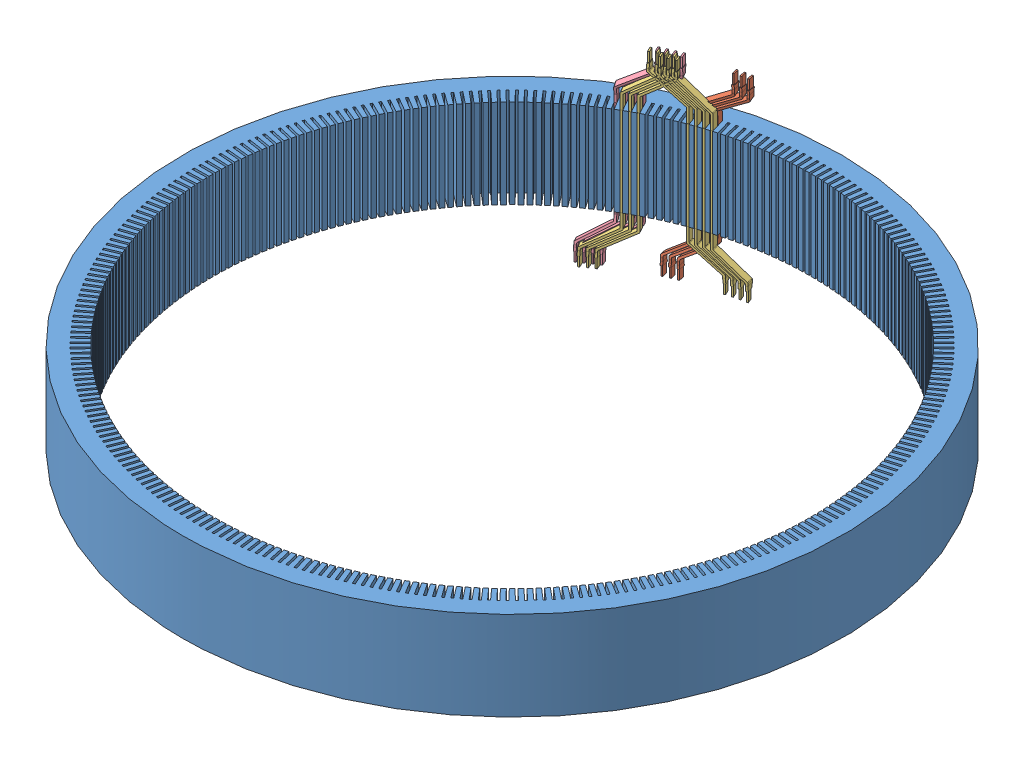
SolidWorks assembly Winding_Diagram_PhaseA, configuration Default. Lengths in mm.
Overall size (6858 2030.15 6858).
15 component instances, 4 part files, 20 mates.
Components (placement in the parent):
- laminasyon35mm_Ns300_Slot22_2022_11_17-1: laminasyon35mm_Ns300_Slot22_2022_11_17 [Default] at (2957.6152 2710.3041 5330.1185) size (6858 925 6858)
- Simetrik Bobin_Aynalanmış Versiyon_Rotordan uzak (BOTTOM) kısım_v03.stp-4: Simetrik Bobin_Aynalanmış Versiyon_Rotordan uzak (BOTTOM) kısım_v03.stp [Default] at (2028.1885 3172.8041 2251.7088) x (0.957319 0 -0.289032) z (0 -1 0) size (612.07 121.36 2007.43)
- Simetrik Bobin_Aynalanmış Versiyon_Rotordan uzak (BOTTOM) kısım_v03.stp-5: Simetrik Bobin_Aynalanmış Versiyon_Rotordan uzak (BOTTOM) kısım_v03.stp [Default] at (1963.923 3172.8041 2271.8484) x (0.951057 0 -0.309017) z (0 -1 0) size (612.07 121.36 2007.43)
- Simetrik Bobin_Aynalanmış Versiyon_Rotordan uzak (BOTTOM) kısım_v03.stp-6: Simetrik Bobin_Aynalanmış Versiyon_Rotordan uzak (BOTTOM) kısım_v03.stp [Default] at (1900.0934 3172.8041 2293.3295) x (0.944376 0 -0.328867) z (0 -1 0) size (612.07 121.36 2007.43)
- Asimetrik Bobin_Rotora yakın (TOP) kısım_v03.stp-5: Asimetrik Bobin_Rotora yakın (TOP) kısım_v03.stp [Default] at (2050.6607 3172.8041 2326.1404) x (0.957319 0 -0.289032) z (0 -1 0) size (644.87 70.38 2007.43)
- Asimetrik Bobin_Rotora yakın (TOP) kısım_v03.stp-6: Asimetrik Bobin_Rotora yakın (TOP) kısım_v03.stp [Default] at (1987.9491 3172.8041 2345.7931) x (0.951057 0 -0.309017) z (0 -1 0) size (644.87 70.38 2007.43)
- Asimetrik Bobin_Rotora yakın (TOP) kısım_v03.stp-7: Asimetrik Bobin_Rotora yakın (TOP) kısım_v03.stp [Default] at (1925.6628 3172.8041 2366.7547) x (0.944376 0 -0.328867) z (0 -1 0) size (644.87 70.38 2007.43)
- Asimetrik Bobin_Rotora yakın (TOP) kısım_v03.stp-8: Asimetrik Bobin_Rotora yakın (TOP) kısım_v03.stp [Default] at (1863.8291 3172.8041 2389.0162) x (0.937282 0 -0.348572) z (0 -1 0) size (644.87 70.38 2007.43)
- Asimetrik Bobin_Aynalanmış Versiyon_Rotordan uzak (BOTTOM) kısım_v03.stp-2: Asimetrik Bobin_Aynalanmış Versiyon_Rotordan uzak (BOTTOM) kısım_v03.stp [Default] at (1467.8148 3172.8041 2480.3931) x (0.886204 0 -0.463296) z (0 -1 0) size (644.87 125.4 2007.43)
- Asimetrik Bobin_Aynalanmış Versiyon_Rotordan uzak (BOTTOM) kısım_v03.stp-3: Asimetrik Bobin_Aynalanmış Versiyon_Rotordan uzak (BOTTOM) kısım_v03.stp [Default] at (1408.4614 3172.8041 2512.2181) x (0.876307 0 -0.481754) z (0 -1 0) size (644.87 125.4 2007.43)
- Asimetrik Bobin_Aynalanmış Versiyon_Rotordan uzak (BOTTOM) kısım_v03.stp-4: Asimetrik Bobin_Aynalanmış Versiyon_Rotordan uzak (BOTTOM) kısım_v03.stp [Default] at (1349.7875 3172.8041 2545.2792) x (0.866025 0 -0.5) z (0 -1 0) size (644.87 125.4 2007.43)
- Asimetrik Bobin_Aynalanmış Versiyon_Rotordan uzak (BOTTOM) kısım_v03.stp-5: Asimetrik Bobin_Aynalanmış Versiyon_Rotordan uzak (BOTTOM) kısım_v03.stp [Default] at (1291.8188 3172.8041 2579.5617) x (0.855364 0 -0.518027) z (0 -1 0) size (644.87 125.4 2007.43)
- Asimetrik Bobin_Rotora yakın (TOP) kısım_v03.stp-9: Asimetrik Bobin_Rotora yakın (TOP) kısım_v03.stp [Default] at (1503.836 3172.8041 2549.2954) x (0.886204 0 -0.463296) z (0 1 0) size (644.87 70.38 2007.43)
- Asimetrik Bobin_Rotora yakın (TOP) kısım_v03.stp-10: Asimetrik Bobin_Rotora yakın (TOP) kısım_v03.stp [Default] at (1445.9177 3172.8041 2580.351) x (0.876307 0 -0.481754) z (0 1 0) size (644.87 70.38 2007.43)
- Asimetrik Bobin_Rotora yakın (TOP) kısım_v03.stp-11: Asimetrik Bobin_Rotora yakın (TOP) kısım_v03.stp [Default] at (1388.6625 3172.8041 2612.6127) x (0.866025 0 -0.5) z (0 1 0) size (644.87 70.38 2007.43)
Mates (geometry in assembly coordinates):
- Parallel6: parallel anti-aligned: plane of laminasyon35mm_Ns300_Slot22_2022_11_17-1 through (2018.0363 3635.3041 2218.083) normal (0.289032 0 0.957319); plane of Simetrik Bobin_Aynalanmış Versiyon_Rotordan uzak (BOTTOM) kısım_v03.stp-4 through (2018.0363 3172.8041 2218.083) normal (-0.289032 0 -0.957319)
- Parallel7: parallel anti-aligned: plane of laminasyon35mm_Ns300_Slot22_2022_11_17-1 through (2968.1457 3635.3041 5326.9392) normal (-0.957319 0 0.289032); plane of Simetrik Bobin_Aynalanmış Versiyon_Rotordan uzak (BOTTOM) kısım_v03.stp-4 through (2028.3753 2710.3041 2214.9614) normal (0.957319 0 -0.289032)
- Distance8: distance = 0.2 mm anti-aligned: plane of laminasyon35mm_Ns300_Slot22_2022_11_17-1 through (2968.1457 3635.3041 5326.9392) normal (-0.957319 0 0.289032); plane of Simetrik Bobin_Aynalanmış Versiyon_Rotordan uzak (BOTTOM) kısım_v03.stp-4 through (2028.3753 2710.3041 2214.9614) normal (0.957319 0 -0.289032)
- Coincident14: coincident anti-aligned: plane of laminasyon35mm_Ns300_Slot22_2022_11_17-1 through (2018.0363 3635.3041 2218.083) normal (0.289032 0 0.957319); plane of Simetrik Bobin_Aynalanmış Versiyon_Rotordan uzak (BOTTOM) kısım_v03.stp-4 through (2018.0363 3172.8041 2218.083) normal (-0.289032 0 -0.957319)
- Distance9: distance = 0.2 mm: line of Simetrik Bobin_Aynalanmış Versiyon_Rotordan uzak (BOTTOM) kısım_v03.stp-4 through (2028.3753 3635.3041 2214.9614) axis (0.289032 0 0.957319); line of laminasyon35mm_Ns300_Slot22_2022_11_17-1 through (2028.5668 3635.3041 2214.9036) axis (0.289032 0 0.957319)
- Parallel10: parallel anti-aligned: plane of Simetrik Bobin_Aynalanmış Versiyon_Rotordan uzak (BOTTOM) kısım_v03.stp-4 through (2038.3408 3172.8041 2285.3347) normal (0.289032 0 0.957319); plane of Asimetrik Bobin_Rotora yakın (TOP) kısım_v03.stp-5 through (2040.5085 3172.8041 2292.5146) normal (-0.289032 0 -0.957319)
- Distance10: distance = 7.5 mm anti-aligned: plane of Asimetrik Bobin_Rotora yakın (TOP) kısım_v03.stp-5 through (2040.5085 3172.8041 2292.5146) normal (-0.289032 0 -0.957319); plane of Simetrik Bobin_Aynalanmış Versiyon_Rotordan uzak (BOTTOM) kısım_v03.stp-4 through (2038.3408 3172.8041 2285.3347) normal (0.289032 0 0.957319)
- Parallel11: parallel anti-aligned: plane of laminasyon35mm_Ns300_Slot22_2022_11_17-1 through (2968.1457 3635.3041 5326.9392) normal (-0.957319 0 0.289032); plane of Asimetrik Bobin_Rotora yakın (TOP) kısım_v03.stp-5 through (2050.8476 2710.3041 2289.393) normal (0.957319 0 -0.289032)
- Distance11: distance = 0.2 mm anti-aligned: plane of Asimetrik Bobin_Rotora yakın (TOP) kısım_v03.stp-5 through (2050.8476 2710.3041 2289.393) normal (0.957319 0 -0.289032); plane of laminasyon35mm_Ns300_Slot22_2022_11_17-1 through (2968.1457 3635.3041 5326.9392) normal (-0.957319 0 0.289032)
- Distance12: distance = 0.2 mm: line of Asimetrik Bobin_Rotora yakın (TOP) kısım_v03.stp-5 through (2051.1164 3635.3041 2290.2833) axis (0.289032 0 0.957319); line of laminasyon35mm_Ns300_Slot22_2022_11_17-1 through (2028.5668 3635.3041 2214.9036) axis (0.289032 0 0.957319)
- Parallel13: parallel anti-aligned: plane of laminasyon35mm_Ns300_Slot22_2022_11_17-1 through (1451.5415 3635.3041 2449.2652) normal (0.463296 0 0.886204); plane of Asimetrik Bobin_Aynalanmış Versiyon_Rotordan uzak (BOTTOM) kısım_v03.stp-2 through (1451.5415 3172.8041 2449.2652) normal (-0.463296 0 -0.886204)
- Parallel14: parallel anti-aligned: plane of laminasyon35mm_Ns300_Slot22_2022_11_17-1 through (2967.3634 3635.3041 5325.0223) normal (-0.886204 0 0.463296); plane of Asimetrik Bobin_Aynalanmış Versiyon_Rotordan uzak (BOTTOM) kısım_v03.stp-2 through (1461.1125 2710.3041 2444.2616) normal (0.886204 0 -0.463296)
- Coincident23: coincident anti-aligned: plane of laminasyon35mm_Ns300_Slot22_2022_11_17-1 through (1451.5415 3635.3041 2449.2652) normal (0.463296 0 0.886204); plane of Asimetrik Bobin_Aynalanmış Versiyon_Rotordan uzak (BOTTOM) kısım_v03.stp-2 through (1451.5415 3172.8041 2449.2652) normal (-0.463296 0 -0.886204)
- Distance13: distance = 0.2 mm anti-aligned: plane of laminasyon35mm_Ns300_Slot22_2022_11_17-1 through (2967.3634 3635.3041 5325.0223) normal (-0.886204 0 0.463296); plane of Asimetrik Bobin_Aynalanmış Versiyon_Rotordan uzak (BOTTOM) kısım_v03.stp-2 through (1461.1125 2710.3041 2444.2616) normal (0.886204 0 -0.463296)
- Distance14: distance = 0.2 mm: line of Asimetrik Bobin_Aynalanmış Versiyon_Rotordan uzak (BOTTOM) kısım_v03.stp-2 through (1461.5434 3635.3041 2445.0858) axis (0.463296 0 0.886204); line of laminasyon35mm_Ns300_Slot22_2022_11_17-1 through (1461.2897 3635.3041 2444.169) axis (0.463296 0 0.886204)
- Parallel16: parallel anti-aligned: plane of Asimetrik Bobin_Aynalanmış Versiyon_Rotordan uzak (BOTTOM) kısım_v03.stp-2 through (1484.088 3172.8041 2511.521) normal (0.463296 0 0.886204); plane of Asimetrik Bobin_Rotora yakın (TOP) kısım_v03.stp-9 through (1487.5628 3172.8041 2518.1675) normal (-0.463296 0 -0.886204)
- Parallel17: parallel anti-aligned: plane of laminasyon35mm_Ns300_Slot22_2022_11_17-1 through (2967.3634 3635.3041 5325.0223) normal (-0.886204 0 0.463296); plane of Asimetrik Bobin_Rotora yakın (TOP) kısım_v03.stp-9 through (1529.6803 3635.3041 2575.4197) normal (0.886204 0 -0.463296)
- Distance15: distance = 0.2 mm anti-aligned: plane of Asimetrik Bobin_Rotora yakın (TOP) kısım_v03.stp-9 through (1529.6803 3635.3041 2575.4197) normal (0.886204 0 -0.463296); plane of laminasyon35mm_Ns300_Slot22_2022_11_17-1 through (2967.3634 3635.3041 5325.0223) normal (-0.886204 0 0.463296)
- Distance16: distance = 0.2 mm: line of Asimetrik Bobin_Rotora yakın (TOP) kısım_v03.stp-9 through (1497.5646 3635.3041 2513.9881) axis (0.463296 0 0.886204); line of laminasyon35mm_Ns300_Slot22_2022_11_17-1 through (1461.2897 3635.3041 2444.169) axis (0.463296 0 0.886204)
- Distance17: distance = 7.5 mm anti-aligned: plane of Asimetrik Bobin_Aynalanmış Versiyon_Rotordan uzak (BOTTOM) kısım_v03.stp-2 through (1484.088 3172.8041 2511.521) normal (0.463296 0 0.886204); plane of Asimetrik Bobin_Rotora yakın (TOP) kısım_v03.stp-9 through (1487.5628 3172.8041 2518.1675) normal (-0.463296 0 -0.886204)
